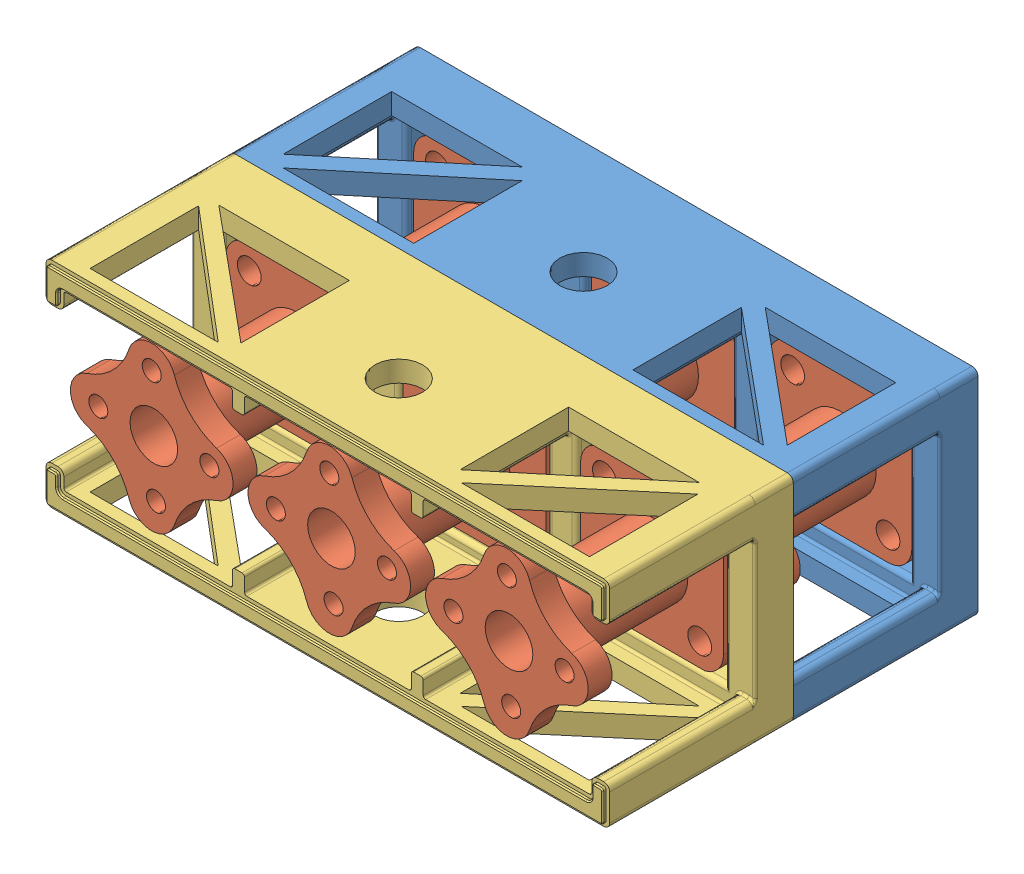
SolidWorks assembly assieme_X1, configuration Default. Lengths in mm.
Overall size (473.32 180 312).
8 component instances, 3 part files, 21 mates.
Components (placement in the parent):
- vassoioX1_sotto-1: vassoioX1_sotto [Default] at (-34.632 11.0465 405.5) size (473.32 180 158)
- X1_n-1: X1_n [Default] at (-181.632 12.0465 415.5) size (136.52 136.52 140)
- X1_n-2: X1_n [Default] at (-32.632 9.0465 415.5) size (136.52 136.52 140)
- X1_n-3: X1_n [Default] at (116.368 13.0415 415.5) size (136.52 136.52 140)
- vassoioX1_componibile-1: vassoioX1_componibile [Default] at (-34.632 11.0465 560.5) size (473.32 180 157)
- X1_n-5: X1_n [Default] at (-184.632 12.0465 570.5) size (136.52 136.52 140)
- X1_n-6: X1_n [Default] at (-35.632 12.0465 570.5) size (136.52 136.52 140)
- X1_n-7: X1_n [Default] at (113.368 12.0465 570.5) size (136.52 136.52 140)
Mates (geometry in assembly coordinates):
- Coincidente1: coincident aligned: plane of X1_n-1 through (-181.632 12.0465 415.5) normal (0 0 -1); plane of X1_n-3 through (116.368 13.0415 415.5) normal (0 0 -1)
- Coincidente2: coincident anti-aligned: plane of vassoio_alto-1 through (-34.632 11.0465 415.5) normal (0 0 1); plane of X1_n-1 through (-181.632 12.0465 415.5) normal (0 0 -1)
- Coincidente3: coincident anti-aligned: plane of vassoio_alto-1 through (-34.632 11.0465 415.5) normal (0 0 1); plane of X1_n-2 through (-32.632 9.0465 415.5) normal (0 0 -1)
- Coincidente4: coincident anti-aligned: plane of vassoio_alto-1 through (-34.632 -47.9535 437.5) normal (0 1 0); plane of X1_n-1 through (-241.632 -47.9535 435.5) normal (0 -1 0)
- Coincidente5: coincident anti-aligned: plane of vassoio_alto-1 through (-34.632 -50.9535 437.5) normal (0 1 0); plane of X1_n-2 through (-92.632 -50.9535 435.5) normal (0 -1 0)
- Coincidente6: coincident anti-aligned: plane of vassoio_alto-1 through (-34.632 -46.9585 437.5) normal (0 1 0); plane of X1_n-3 through (56.368 -46.9585 435.5) normal (0 -1 0)
- Coincidente7: coincident anti-aligned: plane of vassoio_alto-1 through (176.368 11.0465 437.5) normal (-1 0 0); plane of X1_n-3 through (176.368 73.0415 435.5) normal (1 0 0)
- Coincidente8: coincident anti-aligned: plane of vassoio_alto-1 through (27.368 11.0465 437.5) normal (-1 0 0); plane of X1_n-2 through (27.368 69.0465 435.5) normal (1 0 0)
- Coincidente10: coincident anti-aligned: plane of vassoio_alto-1 through (-121.632 11.0465 437.5) normal (-1 0 0); plane of X1_n-1 through (-121.632 72.0465 435.5) normal (1 0 0)
- Distanza1: distance = 1 mm anti-aligned: plane of vassoioX1_sotto-1 through (184.868 81.5465 563.5) normal (0 0 1); plane of vassoioX1_componibile-1 through (184.868 81.5465 564.5) normal (0 0 -1)
- Coincidente12: coincident anti-aligned: plane of vassoioX1_sotto-1 through (196.868 98.0465 563.5) normal (0 1 0); plane of vassoioX1_componibile-1 through (196.868 98.0465 564.5) normal (0 -1 0)
- Coincidente14: coincident anti-aligned: plane of vassoioX1_sotto-1 through (-268.132 96.0465 563.5) normal (-1 0 0); plane of vassoioX1_componibile-1 through (-268.132 96.0465 564.5) normal (1 0 0)
- Coincidente15: coincident anti-aligned: plane of vassoioX1_componibile-1 through (-34.632 11.0465 570.5) normal (0 0 1); plane of X1_n-7 through (113.368 12.0465 570.5) normal (0 0 -1)
- Coincidente16: coincident anti-aligned: plane of vassoioX1_componibile-1 through (-34.632 11.0465 570.5) normal (0 0 1); plane of X1_n-6 through (-35.632 12.0465 570.5) normal (0 0 -1)
- Coincidente17: coincident anti-aligned: plane of vassoioX1_componibile-1 through (-34.632 11.0465 570.5) normal (0 0 1); plane of X1_n-5 through (-184.632 12.0465 570.5) normal (0 0 -1)
- Distanza2: distance = 1 mm anti-aligned: plane of X1_n-5 through (-244.632 72.0465 590.5) normal (-1 0 0); plane of vassoioX1_componibile-1 through (-245.632 11.0465 592.5) normal (1 0 0)
- Distanza4: distance = 1 mm anti-aligned: plane of X1_n-6 through (-95.632 72.0465 590.5) normal (-1 0 0); plane of vassoioX1_componibile-1 through (-96.632 11.0465 592.5) normal (1 0 0)
- Distanza5: distance = 1 mm anti-aligned: plane of vassoioX1_componibile-1 through (52.368 11.0465 592.5) normal (1 0 0); plane of X1_n-7 through (53.368 72.0465 590.5) normal (-1 0 0)
- Coincidente22: coincident aligned: plane of X1_n-6 through (-95.632 72.0465 590.5) normal (0 1 0); plane of X1_n-7 through (53.368 72.0465 590.5) normal (0 1 0)
- Coincidente23: coincident aligned: plane of X1_n-5 through (-244.632 72.0465 590.5) normal (0 1 0); plane of X1_n-6 through (-95.632 72.0465 590.5) normal (0 1 0)
- Distanza6: distance = 1 mm anti-aligned: plane of X1_n-5 through (-244.632 72.0465 590.5) normal (0 1 0); plane of vassoioX1_componibile-1 through (-34.632 73.0465 592.5) normal (0 -1 0)
